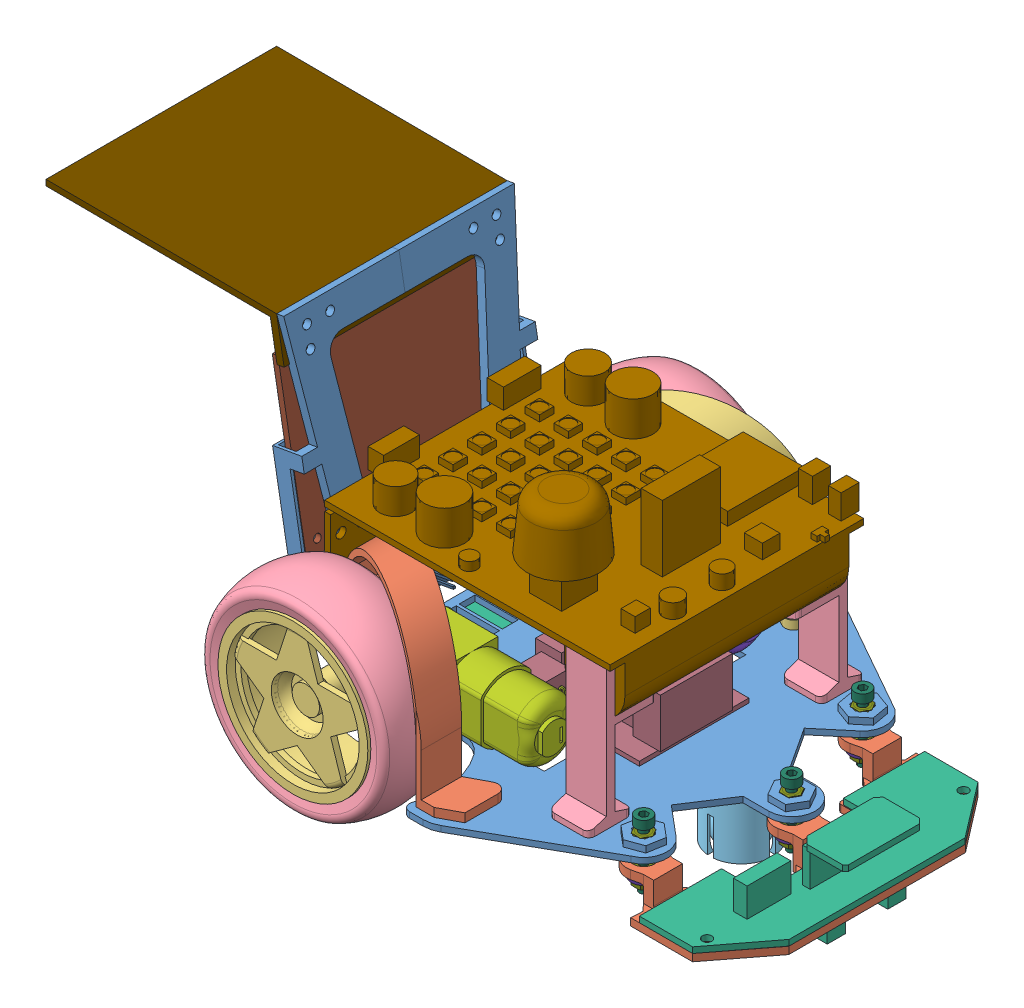
SolidWorks assembly Montagem_chassis_ajuste_m3, configuration Valor predeterminado. Lengths in mm.
Overall size (250.56 134.61 148.4).
46 component instances, 25 part files, 91 mates.
Components (placement in the parent):
- chassis_com_ajuste_m3-3: chassis_com_ajuste_m3 [Valor predeterminado] at origin size (130.17 20 141)
- suporte_sensores_com_ajuste_m3-3: suporte_sensores_com_ajuste_m3 [Valor predeterminado] at (138.3 -13.75 0) size (49 11.25 99)
- roda-1: roda [Valor predeterminado] at (16.43 13.18 70.62) x (0 0 -1) z (1 0 0) size (32 68 68)
  - aro-2: aro [Valor predeterminado] at origin size (32 52 52)
  - pneu-2: pneu [Valor predeterminado] at (-0.45 0 0) size (23.96 68 68)
- roda-2: roda [Valor predeterminado] at (16.43 13.18 -70.62) x (0 0 1) z (-1 0 0) size (32 68 68)
  - aro-2: aro [Valor predeterminado] at origin size (32 52 52)
  - pneu-2: pneu [Valor predeterminado] at (-0.45 0 0) size (23.96 68 68)
- esfera_apoio-1: esfera_apoio [Valor predeterminado] at (101.4386 -21.67 0) size (21.6 21.67 21.6)
- Placa_sensores_reflexivos-1: Placa_sensores_reflexivos [Valor predeterminado] at (132 -12.5 0) x (0 0 1) z (-1 0 0) size (99 26 34.88)
- motor_redutor-1: motor_redutor [Valor predeterminado] at (35 13.25 34.5) x (0 0 -1) z (1 0 0) size (36.88 22.5 65.85)
- esq_motor_redutor-2: esq_motor_redutor [Valor predeterminado] at (35 13.25 -34.5) x (0 0 1) z (-1 0 0) size (36.88 22.5 65.85)
- placa_BitDogLab-1: placa_BitDogLab [Valor predeterminado] at (50.3609 52.4 0) x (0 0 -1) z (1 0 0) size (89.54 57.4 101.27)
- Placa_expansor_I2C_v2-1: Placa_expansor_I2C_v2 [Valor predeterminado] at (-3.9802 16.8143 0) x (0 0 1) z (-0.173648 0.984808 0) size (32.5 13.5 19.5)
- Placa_monitoramento_corrente-1: Placa_monitoramento_corrente [Valor predeterminado] at (-15.88 55.8408 0) x (0 0 -1) z (-0.173648 0.984808 0) size (77 6 57.5)
- parafusoMotor-1: parafusoMotor [Valor predeterminado] at (36.3 4.34 45) x (0 0 -1) z (1 0 0) size (30 5 5)
- parafusoMotor-2: parafusoMotor [Valor predeterminado] at (36.3 4.34 -44.8) x (0 0 1) z (-1 0 0) size (30 5 5)
- Placa_MotorDriver-1: Placa_MotorDriver [Valor predeterminado] at (62 4 0) size (50.8 18.5 38)
- Placa_modulo_bluetooth-2: Placa_modulo_bluetooth [Valor predeterminado] at (-33.6334 51.4274 -23.0988) x (0.984808 0.173648 0) z (0 0 1) size (32.5 2 19.5)
- M3_assembly-1: M3_assembly [Valor predeterminado] at (105.5 9.4 38) size (8.5 23 8.5)
  - M3_cap_screw-1: M3_cap_screw [Valor predeterminado] at origin size (5.5 23 5.5)
  - M3_nut-1: M3_nut [Valor predeterminado] at (0 -7.4 0) size (6.35 3.17 5.5)
  - M3_nut-2: M3_nut [Valor predeterminado] at (0 -20.9 0) size (6.35 3.17 5.5)
  - M3_nut-3: M3_nut [Valor predeterminado] at (0 -17 0) size (6.35 3.17 5.5)
  - arruela_m3-1: arruela_m3 [Valor predeterminado] at (0 -18.5 0) size (8.5 1.5 8.5)
- M3_assembly-4: M3_assembly [Valor predeterminado] at (118.84 9.4 0) size (8.5 23 8.5)
  - M3_cap_screw-1: M3_cap_screw [Valor predeterminado] at origin size (5.5 23 5.5)
  - M3_nut-1: M3_nut [Valor predeterminado] at (0 -7.4 0) size (6.35 3.17 5.5)
  - M3_nut-2: M3_nut [Valor predeterminado] at (0 -20.9 0) size (6.35 3.17 5.5)
  - M3_nut-3: M3_nut [Valor predeterminado] at (0 -17 0) size (6.35 3.17 5.5)
  - arruela_m3-1: arruela_m3 [Valor predeterminado] at (0 -18.5 0) size (8.5 1.5 8.5)
- M3_assembly-3: M3_assembly [Valor predeterminado] at (105.5 9.4 -38) size (8.5 23 8.5)
  - M3_cap_screw-1: M3_cap_screw [Valor predeterminado] at origin size (5.5 23 5.5)
  - M3_nut-1: M3_nut [Valor predeterminado] at (0 -7.4 0) size (6.35 3.17 5.5)
  - M3_nut-2: M3_nut [Valor predeterminado] at (0 -20.9 0) size (6.35 3.17 5.5)
  - M3_nut-3: M3_nut [Valor predeterminado] at (0 -17 0) size (6.35 3.17 5.5)
  - arruela_m3-1: arruela_m3 [Valor predeterminado] at (0 -18.5 0) size (8.5 1.5 8.5)
- Aerofolio-1: Aerofolio [Default] at (-17.2221 83.2745 -40) x (0 0 1) z (-0.984808 -0.173648 0) size (80 29.29 79.07)
- Suporte_Aerofolio2-1: Suporte_Aerofolio2 [Valor predeterminado] at (-11.6344 65.9821 0) x (0 0 -1) z (0.984808 0.173648 0) size (80 100 10.94) (hidden)
- Suporte_Aerofolio3-1: Suporte_Aerofolio3 [Valor predeterminado] at (-2.9544 -0.5209 0) x (0 0 -1) z (0.984808 0.173648 0) size (81 100 10.3)
- paralama-1: paralama [Valor predeterminado] at (29.5701 19.9 53.6334) x (0.882948 0 0.469472) z (-0.469472 0 0.882948) size (79.74 50.4 22.99)
- paralama_esquerdo_v2-2: paralama_esquerdo_v2 [Valor predeterminado] at (29.5701 19.9 -53.6334) x (0.882948 0 -0.469472) z (0.469472 0 0.882948) size (79.74 50.4 22.99)
- suporte_frontal_BitDog-1: suporte_frontal_BitDog [Valor predeterminado] at (89.3609 2 40.33) x (0 0 -1) z (1 0 0) size (23 50.4 14)
- suporte_frontal_BitDog-2: suporte_frontal_BitDog [Valor predeterminado] at (89.3609 2 -40.33) x (0 0 1) z (-1 0 0) size (23 50.4 14)
- suporte_adaptador_i2c-1: suporte_adaptador_i2c [Valor predeterminado] at (-5.7529 15.35 0) x (0 0 1) z (-0.173648 0.984808 0) size (36.5 2 19.5)
- bateria_motor-1: bateria_motor [Valor predeterminado] at (45 -5 0) x (0 0 -1) z (1 0 0) size (25 10 90)
Mates (geometry in assembly coordinates):
- Distância4: distance = 124 mm aligned: plane of chassis-2 through (0.4379 0.5122 -124) normal (0 0 1)
- Distância5: distance = 124 mm aligned: plane of chassis-4 through (163.4129 -1.1812 -124) normal (0 0 1)
- Coincidente13: coincident aligned: plane of chassis-4 through (163.4129 -1.1812 -124) normal (0 0 1); plane of suporte_sensores_avulsos-2 through (288.424 -15.4312 -124) normal (0 0 1)
- Distância7: distance = 1 mm anti-aligned: plane of sensor_individual-13 through (266.733 0.5149 -102) normal (0 0 -1); plane of chassis-4 through (279.4129 0.8188 -103) normal (0 0 1)
- Coincidente18: coincident aligned: plane of suporte_sensores_com_ajuste_m3-3 through (138.3 -13.75 0) normal (0 0 1)
- Distância18: distance = 1 mm anti-aligned: plane of sensor_individual-9 through (135.4345 -11.5 16.3209) normal (0 -1 0); plane of suporte_sensores_com_ajuste_m3-3 through (138.3 -12.5 0) normal (0 1 0)
- Coincidente38: coincident aligned: plane of esfera_apoio-1 through (101.4386 -21.67 0) normal (0 0 1)
- Coincidente43: coincident anti-aligned: plane of parafuso_ajuste_10mm-1 through (102.8368 -11.3 38) normal (0 1 0); plane of anel_trava_ajuste-5 through (102.8368 -11.3 38) normal (0 -1 0)
- Coincidente44: coincident anti-aligned: plane of parafuso_ajuste_10mm-1 through (102.8368 -16.3 38) normal (0 -1 0); plane of anel_trava_ajuste-6 through (102.8368 -16.3 38) normal (0 1 0)
- Coincidente45: coincident anti-aligned: plane of parafuso_ajuste_10mm-3 through (118.8368 -16.3 0) normal (0 -1 0); plane of anel_trava_ajuste-3 through (118.8368 -16.3 0) normal (0 1 0)
- Coincidente46: coincident anti-aligned: plane of parafuso_ajuste_10mm-3 through (118.8368 -11.3 0) normal (0 1 0); plane of anel_trava_ajuste-4 through (118.8368 -11.3 0) normal (0 -1 0)
- Coincidente47: coincident anti-aligned: plane of parafuso_ajuste_10mm-2 through (102.8368 -16.3 -38) normal (0 -1 0); plane of anel_trava_ajuste-1 through (102.8368 -16.3 -38) normal (0 1 0)
- Coincidente48: coincident anti-aligned: plane of parafuso_ajuste_10mm-2 through (102.8368 -11.3 -38) normal (0 1 0); plane of anel_trava_ajuste-2 through (102.8368 -11.3 -38) normal (0 -1 0)
- Concêntrico4: concentric aligned: cylinder of parafuso_ajuste_10mm-2 through (102.8368 -23.3903 -38) axis (0 -1 0) radius 0.8013; cylinder of anel_trava_ajuste-1 through (102.8368 -16.3 -38) axis (0 -1 0) radius 0.8
- Concêntrico5: concentric aligned: cylinder of parafuso_ajuste_10mm-2 through (102.8368 -23.3903 -38) axis (0 -1 0) radius 0.8013; cylinder of anel_trava_ajuste-2 through (102.8368 -10.55 -38) axis (0 -1 0) radius 0.8
- Concêntrico6: concentric aligned: cylinder of parafuso_ajuste_10mm-1 through (102.8368 -23.3903 38) axis (0 -1 0) radius 0.8013; cylinder of anel_trava_ajuste-6 through (102.8368 -16.3 38) axis (0 -1 0) radius 0.8
- Concêntrico7: concentric aligned: cylinder of parafuso_ajuste_10mm-1 through (102.8368 -23.3903 38) axis (0 -1 0) radius 0.8013; cylinder of anel_trava_ajuste-5 through (102.8368 -10.55 38) axis (0 -1 0) radius 0.8
- Concêntrico8: concentric aligned: cylinder of parafuso_ajuste_10mm-3 through (118.8368 -23.3903 0) axis (0 -1 0) radius 0.8013; cylinder of anel_trava_ajuste-3 through (118.8368 -16.3 0) axis (0 -1 0) radius 0.8
- Concêntrico9: concentric aligned: cylinder of parafuso_ajuste_10mm-3 through (118.8368 -23.3903 0) axis (0 -1 0) radius 0.8013; cylinder of anel_trava_ajuste-4 through (118.8368 -10.55 0) axis (0 -1 0) radius 0.8
- Concêntrico12: concentric: cylinder of chassis_com_ajuste-3 through (102.8015 4.5 38.0405) axis (0 -1 0) radius 6; cylinder of parafuso_ajuste_10mm-1 through (102.8368 -23.3903 38) axis (0 -1 0) radius 1.6025
- Coincidente50: coincident aligned: plane of chassis_com_ajuste_m3-3 through (0 0 0) normal (0 0 1)
- Coincidente51: coincident aligned: plane of chassis_com_ajuste_m3-3 through (0 0 0) normal (0 1 0)
- Coincidente52: coincident aligned: plane of chassis_com_ajuste_m3-3 through (0 0 0) normal (1 0 0)
- Ângulo1: planar angle = 5.585054 rad aligned: plane of parafuso_ajuste_10mm-1 through (102.8368 15 38) normal (0.642788 0 0.766044)
- Ângulo2: planar angle = 5.585054 rad aligned: plane of parafuso_ajuste_10mm-3 through (118.8368 15 0) normal (-0.642788 0 0.766044)
- Coincidente58: coincident aligned: plane of Placa_sensores_reflexivos-1 through (132 -12.5 0) normal (0 0 1)
- Coincidente62: coincident anti-aligned: plane of chassis_com_ajuste_m3-3 through (10.4471 17.5086 25) normal (0 0 1); plane of motor_redutor-1 through (9 20.5 25) normal (0 0 -1)
- Coincidente63: coincident anti-aligned: plane of chassis_com_ajuste_m3-3 through (105.5 2 38) normal (0 1 0); plane of motor_redutor-1 through (53.5 2 25) normal (0 -1 0)
- Coincidente67: coincident anti-aligned: plane of placa_BitDogLab-1 through (50.3609 52.4 0) normal (0 0 -1)
- Concêntrico13: concentric anti-aligned: cylinder of roda-1/aro-2 through (16.43 13.18 35.2504) axis (0 0 1) radius 4.75; cylinder of motor_redutor-1 through (16.43 13.18 52.94) axis (0 0 -1) radius 2.72
- Distância36: distance = 21.62 mm aligned: plane of roda-1/aro-2 through (16.43 36.18 46.62) normal (0 0 -1); plane of motor_redutor-1 through (9 20.5 25) normal (0 0 -1)
- Paralelo1: parallel aligned: plane of roda-1 through (16.43 13.18 70.62) normal (1 0 0)
- Coincidente70: coincident anti-aligned: plane of roda-1 through (16.43 13.18 70.62) normal (1 0 0); plane of roda-2 through (16.43 13.18 -70.62) normal (-1 0 0)
- Coincidente71: coincident aligned: plane of roda-1 through (16.43 13.18 70.62) normal (0 1 0); plane of roda-2 through (16.43 13.18 -70.62) normal (0 1 0)
- Simétrico1: symmetric aligned: plane of roda-1 through (16.43 13.18 70.62) normal (0 0 -1); plane of roda-2 through (16.43 13.18 -70.62) normal (0 0 1)
- Coincidente74: coincident anti-aligned: plane of Placa_monitoramento_corrente-1 through (-15.88 55.8408 0) normal (0 0 -1)
- Concêntrico14: concentric anti-aligned: cylinder of motor_redutor-1 through (36.3 4.34 16.06) axis (0 0 1) radius 1.5; cylinder of parafusoMotor-1 through (36.3 4.34 45) axis (0 0 -1) radius 1.25
- Concêntrico15: concentric anti-aligned: cylinder of esq_motor_redutor-2 through (36.3 4.34 -16.06) axis (0 0 -1) radius 1.5; cylinder of parafusoMotor-2 through (36.3 4.34 -44.8) axis (0 0 1) radius 1.25
- Distância37: distance = 1 mm aligned: plane of parafusoMotor-1 through (34.117 4.34 45) normal (0 0 1); plane of motor_redutor-1 through (9 20.5 44) normal (0 0 1)
- Distância38: distance = 0.8 mm aligned: plane of parafusoMotor-2 through (38.483 4.34 -44.8) normal (0 0 -1); plane of esq_motor_redutor-2 through (9 20.5 -44) normal (0 0 -1)
- Paralelo2: parallel anti-aligned: plane of parafusoMotor-2 through (36.3 4.34 -44.8) normal (-1 0 0)
- Paralelo3: parallel aligned: plane of parafusoMotor-1 through (36.3 4.34 45) normal (1 0 0)
- Distância39: distance = 5 mm aligned: plane of motor_redutor-1 through (5 20.5 25) normal (-1 0 0); plane of chassis_com_ajuste_m3-3 through (0 2 -38) normal (-1 0 0)
- Distância40: distance = 2 mm anti-aligned: plane of Placa_MotorDriver-1 through (62 4 0) normal (0 -1 0); plane of chassis_com_ajuste_m3-3 through (105.5 2 38) normal (0 1 0)
- Concêntrico16: concentric aligned: cylinder of chassis_com_ajuste_m3-3 through (69 9 -15.3) axis (0 -1 0) radius 1.25; cylinder of Placa_MotorDriver-1 through (69 5.5 -15.3) axis (0 -1 0) radius 2
- Distância41: distance = 2 mm anti-aligned: plane of Placa_monitoramento_corrente-1 through (-17.8496 55.4935 0) normal (-0.984808 -0.173648 0); plane of Suporte_Aerofolio2-1 through (-16.2161 34.7115 40) normal (0.984808 0.173648 0)
- Coincidente88: coincident anti-aligned: plane of Placa_monitoramento_corrente-2 through (-42.044 72.0117 0) normal (0 0 -1)
- Coincidente89: coincident anti-aligned: plane of Placa_monitoramento_corrente-1 through (-17.8496 55.4935 0) normal (-0.984808 -0.173648 0); plane of Placa_expansor_I2C-2 through (-17.9775 56.2188 -13.3488) normal (0.984808 0.173648 0)
- Concêntrico17: concentric anti-aligned: cylinder of chassis_com_ajuste_m3-3 through (105.5 2 38) axis (0 -1 0) radius 1.75; cylinder of M3_assembly-1/M3_cap_screw-1 through (105.5 -13.6 38) axis (0 1 0) radius 1.5
- Concêntrico19: concentric anti-aligned: cylinder of chassis_com_ajuste_m3-3 through (105.5 2 -38) axis (0 -1 0) radius 1.75; cylinder of M3_assembly-3/M3_cap_screw-1 through (105.5 -13.6 -38) axis (0 1 0) radius 1.5
- Coincidente90: coincident anti-aligned: plane of chassis_com_ajuste_m3-3 through (105.5 2 38) normal (0 1 0); plane of M3_assembly-1/M3_nut-1 through (105.5 2 38) normal (0 -1 0)
- Coincidente93: coincident anti-aligned: plane of Suporte_Aerofolio2-1 through (-14.0964 65.548 0) normal (-0.984808 -0.173648 0); plane of Aerofolio-1 through (-18.5245 90.6606 40) normal (0.984808 0.173648 0)
- Coincidente95: coincident anti-aligned: plane of assembly through (0 0 0) normal (0 0 1); plane of Aerofolio-1 through (-17.2221 83.2745 0) normal (0 0 -1)
- Coincidente96: coincident anti-aligned: plane of chassis_com_ajuste_m3-3 through (0 0 45.7777) normal (-0.984808 -0.173648 0); plane of Suporte_Aerofolio2-1 through (-11.6344 65.9821 0) normal (0.984808 0.173648 0)
- Coincidente97: coincident: line of Aerofolio-1 through (-19.8268 98.0467 40) axis (0 0 -1); plane of Suporte_Aerofolio2-1 through (-17.3648 98.4808 40) normal (-0.173648 0.984808 0)
- Coincidente98: coincident anti-aligned: plane of Suporte_Aerofolio2-1 through (-11.6344 65.9821 0) normal (0 0 -1)
- Coincidente99: coincident: plane of chassis_com_ajuste_m3-3 through (105.5 0 38) normal (0 -1 0); line of Suporte_Aerofolio2-1 through (0 0 9) axis (0 0 1)
- Coincidente100: coincident: plane of chassis_com_ajuste_m3-3 through (0 0 45.7777) normal (-0.984808 -0.173648 0); plane of Suporte_Aerofolio3-1 through (0 0 39.0994) normal (0.984808 0.173648 0)
- Coincidente101: coincident: line of chassis_com_ajuste_m3-3 through (0 0 27.5) axis (0 0 -1); line of Suporte_Aerofolio3-1 through (0 0 75.2662) axis (0 0 -1)
- Coincidente102: coincident anti-aligned: plane of Suporte_Aerofolio3-1 through (-2.9544 -0.5209 0) normal (0 0 -1)
- Coincidente103: coincident aligned: plane of suporte_sensores_com_ajuste_m3-3 through (148.5 -12.5 0) normal (1 0 0); plane of Placa_sensores_reflexivos-1 through (148.5 -10.5 30.5) normal (1 0 0)
- Concêntrico22: concentric aligned: cylinder of suporte_sensores_com_ajuste_m3-3 through (105.5 -6.75 38) axis (0 1 0) radius 3.75; cylinder of M3_assembly-1/M3_cap_screw-1 through (105.5 -13.6 38) axis (0 1 0) radius 1.5
- Coincidente104: coincident aligned: plane of M3_assembly-1 through (105.5 9.4 38) normal (0 1 0); plane of M3_assembly-3 through (105.5 9.4 -38) normal (0 1 0)
- Coincidente106: coincident aligned: plane of M3_assembly-1 through (105.5 9.4 38) normal (0 1 0); plane of M3_assembly-4 through (118.84 9.4 0) normal (0 1 0)
- Distância43: distance = 2 mm anti-aligned: plane of Placa_expansor_I2C_v2-1 through (-3.7037 26.7635 -16.25) normal (-0.173648 0.984808 0); plane of Placa_monitoramento_corrente-1 through (-12.8573 27.1803 38.5) normal (0.173648 -0.984808 0)
- Coincidente110: coincident aligned: plane of Placa_expansor_I2C_v2-1 through (-3.9802 16.8143 0) normal (0 0 1)
- Distância42: distance = 3 mm anti-aligned: plane of Placa_monitoramento_corrente-1 through (-12.8573 27.1803 38.5) normal (0.173648 -0.984808 0); plane of Suporte_Aerofolio3-1 through (-7.4693 25.0841 0) normal (-0.173648 0.984808 0)
- Coincidente112: coincident: line of chassis_com_ajuste_m3-3 through (0 0 27.5) axis (0 0 -1); plane of Suporte_Aerofolio3-1 through (0 0 0) normal (0.173648 -0.984808 0)
- Coincidente113: coincident anti-aligned: plane of chassis_com_ajuste_m3-3 through (0 0 45.7777) normal (-0.984808 -0.173648 0); plane of Suporte_Aerofolio3-1 through (0 0 0) normal (0.984808 0.173648 0)
- Distância46: distance = 56.5 mm aligned: plane of paralama-1 through (56.5 19.9 67.9523) normal (-1 0 0); plane of chassis_com_ajuste_m3-3 through (0 2 -38) normal (-1 0 0)
- Coincidente118: coincident anti-aligned: plane of placa_BitDogLab-1 through (0.8609 28 -44) normal (0 -1 0); plane of paralama-1 through (0.1679 28 38) normal (0 1 0)
- Coincidente119: coincident anti-aligned: plane of chassis_com_ajuste_m3-3 through (105.5 2 38) normal (0 1 0); plane of paralama-1 through (69.7442 2 74.9944) normal (0 -1 0)
- Coincidente121: coincident anti-aligned: plane of placa_BitDogLab-1 through (2.8609 51 -44) normal (1 0 0); plane of paralama-1 through (2.8609 28 39.4319) normal (-1 0 0)
- Tangente1: tangent anti-aligned: plane of chassis_com_ajuste_m3-3 through (0 2 38) normal (0 0 1); cylinder of paralama-1 through (73.0429 2 142.6943) axis (-1 0 0) radius 104.6943
- Coincidente123: coincident anti-aligned: plane of chassis_com_ajuste_m3-3 through (105.5 2 38) normal (0 1 0); plane of suporte_frontal_BitDog-1 through (96.3609 2 40.33) normal (0 -1 0)
- Distância48: distance = 5 mm: plane of suporte_frontal_BitDog-2 through (94.8609 2 -44.5) normal (1 0 0); plane of placa_BitDogLab-1 through (99.8609 54.4 44) normal (1 0 0)
- Coincidente127: coincident anti-aligned: plane of chassis_com_ajuste_m3-3 through (105.5 2 38) normal (0 1 0); plane of suporte_frontal_BitDog-2 through (82.3609 2 -40.33) normal (0 -1 0)
- Coincidente128: coincident anti-aligned: plane of placa_BitDogLab-1 through (0.8609 54.4 44) normal (0 0 1); plane of suporte_frontal_BitDog-1
- Coincidente129: coincident: plane of placa_BitDogLab-1 through (0.8609 54.4 -44) normal (0 0 -1); plane of suporte_frontal_BitDog-2 through (93.2707 2 -44) normal (0 0 1)
- Coincidente130: coincident: plane of placa_BitDogLab-1 through (0.8609 54.4 44) normal (0 0 1); plane of suporte_frontal_BitDog-1 through (96.7709 2 44) normal (0 0 -1)
- Concêntrico23: concentric aligned: cylinder of placa_BitDogLab-1 through (89.3609 42.4 -38.83) axis (0 0 1) radius 10.5; cylinder of suporte_frontal_BitDog-1 through (89.3609 42.4 24.83) axis (0 0 1) radius 10.5
- Coincidente131: coincident anti-aligned: plane of placa_BitDogLab-1 through (89.3609 42.4 38.83) normal (0 0 1); plane of suporte_frontal_BitDog-1 through (96.3609 2 38.83) normal (0 0 -1)
- Coincidente132: coincident anti-aligned: plane of placa_BitDogLab-1 through (89.3609 42.4 -38.83) normal (0 0 -1); plane of suporte_frontal_BitDog-2 through (82.3609 2 -38.83) normal (0 0 1)
- Concêntrico24: concentric anti-aligned: cylinder of placa_BitDogLab-1 through (89.3609 42.4 -38.83) axis (0 0 1) radius 10.5; cylinder of suporte_frontal_BitDog-2 through (89.3609 42.4 -24.83) axis (0 0 -1) radius 10.5
- Coincidente134: coincident anti-aligned: plane of Placa_expansor_I2C_v2-1 through (-3.9802 16.8143 0) normal (-0.984808 -0.173648 0); plane of suporte_adaptador_i2c-1 through (-3.7833 15.6973 0) normal (0.984808 0.173648 0)
- Coincidente135: coincident aligned: plane of suporte_adaptador_i2c-1 through (-5.7529 15.35 0) normal (0 0 1)
- Coincidente136: coincident aligned: plane of Suporte_Aerofolio3-1 through (-2.9544 -0.5209 0) normal (-0.984808 -0.173648 0); plane of suporte_adaptador_i2c-1 through (-5.7529 15.35 0) normal (-0.984808 -0.173648 0)
- Coincidente139: coincident anti-aligned: plane of bateria_motor-1 through (45 -5 0) normal (0 0 -1)
- Coincidente140: coincident aligned: plane of chassis_com_ajuste_m3-3 through (0 2 -38) normal (-1 0 0); plane of bateria_motor-1 through (0 -5 7.5) normal (-1 0 0)
- Coincidente141: coincident anti-aligned: plane of chassis_com_ajuste_m3-3 through (105.5 0 38) normal (0 -1 0); plane of bateria_motor-1 through (90 0 7.5) normal (0 1 0)
- Coincidente142: coincident anti-aligned: plane of chassis_com_ajuste_m3-3 through (105.5 0 38) normal (0 -1 0); plane of esfera_apoio-1 through (112.2386 0 0) normal (0 1 0)
